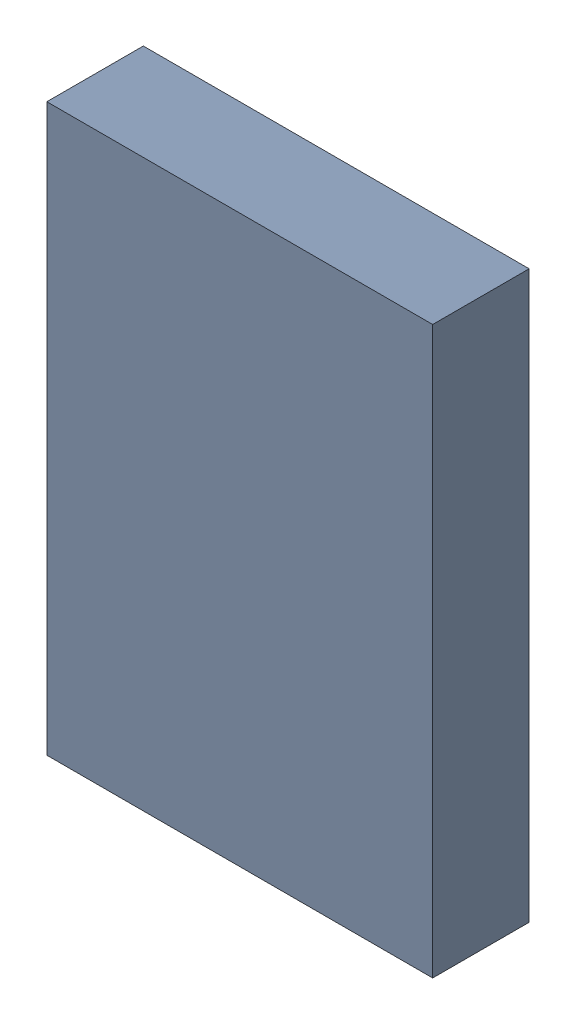
SolidWorks assembly 6327400384, configuration Default. Lengths in mm.
Overall size (3 4.4 0.75).
2 component instances, 1 part files, 0 mates.
Components (placement in the parent):
- 6701982208-1:  [Default] at (27.7 14.8 0) (suppressed, hidden)
- Extruded-23-1: Extruded-23 [Default] at origin size (3 4.4 0.75)
